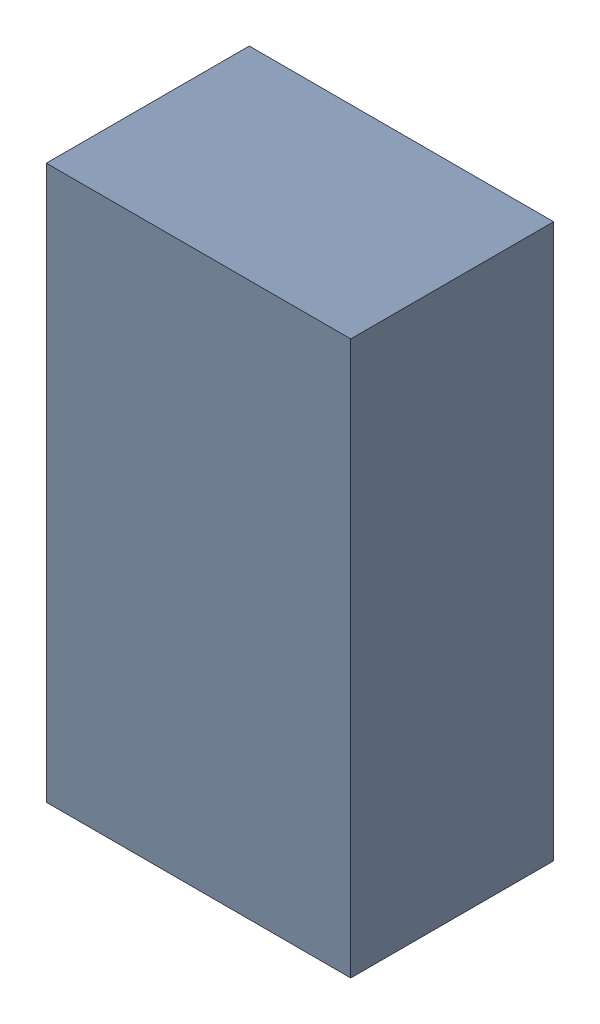
SolidWorks assembly D300_2PCB, configuration Default. Lengths in mm.
Overall size (1.65 3 1.1).
2 component instances, 1 part files, 0 mates.
Components (placement in the parent):
- 846487096-1: 846487096 [Default] at (155.7253 101.5181 0) size (1.65 3 1.1)
  - Extruded_36-1: Extruded_36 [Default] at origin size (1.65 3 1.1)
